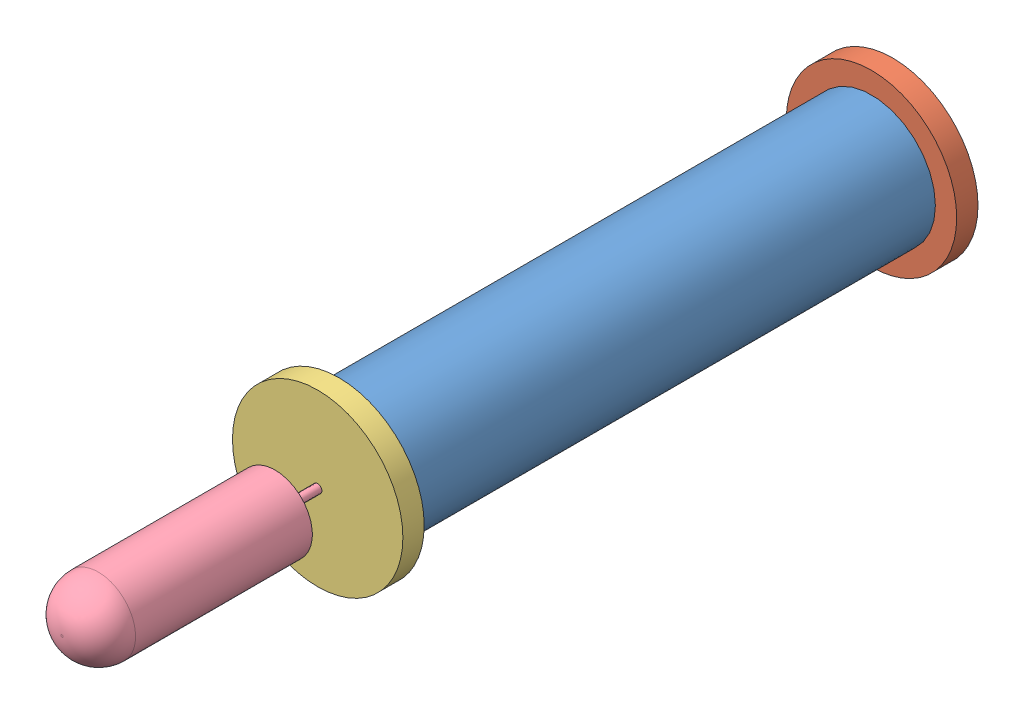
SolidWorks assembly Assemblage1, configuration Défaut. Lengths in mm.
Overall size (80 80 390).
4 component instances, 4 part files, 6 mates.
Components (placement in the parent):
- PVC de 60mm-1: PVC de 60mm [Défaut] at (-3.9084 -2.2274 250) size (60 60 250)
- bouchon bas-1: bouchon bas [Défaut] at (-3.9084 -2.2274 250) size (80 80 30)
- Bouchon haut-1: Bouchon haut [Défaut] at (-3.9084 -2.2274 480) size (80 80 40)
- micro-1: micro [Défaut] at (-3.9084 -2.2274 630) x (1 0 0) z (0 0 -1) size (35 35 125)
Mates (geometry in assembly coordinates):
- Coaxiale1: concentric aligned: cylinder of PVC de 60mm-1 through (-3.9084 -2.2274 500) axis (0 0 -1) radius 29; cylinder of bouchon bas-1 through (-3.9084 -2.2274 270) axis (0 0 -1) radius 29
- Coïncidente1: coincident anti-aligned: plane of PVC de 60mm-1 through (-3.9084 -2.2274 250) normal (0 0 -1); plane of bouchon bas-1 through (-3.9084 -2.2274 250) normal (0 0 1)
- Coaxiale2: concentric aligned: cylinder of PVC de 60mm-1 through (-3.9084 -2.2274 500) axis (0 0 -1) radius 29; cylinder of Bouchon haut-1 through (-3.9084 -2.2274 500) axis (0 0 -1) radius 29
- Coïncidente2: coincident anti-aligned: plane of PVC de 60mm-1 through (-3.9084 -2.2274 500) normal (0 0 1); plane of Bouchon haut-1 through (-3.9084 -2.2274 500) normal (0 0 -1)
- Coaxiale3: concentric aligned: cylinder of Bouchon haut-1 through (-3.9084 -2.2274 474.3431) axis (0 0 1) radius 2; cylinder of micro-1 through (-3.9084 -2.2274 505) axis (0 0 1) radius 2
- Distance1: distance = 20 mm anti-aligned: plane of micro-1 through (-3.9084 -2.2274 530) normal (0 0 -1); plane of Bouchon haut-1 through (-3.9084 -2.2274 510) normal (0 0 1)
